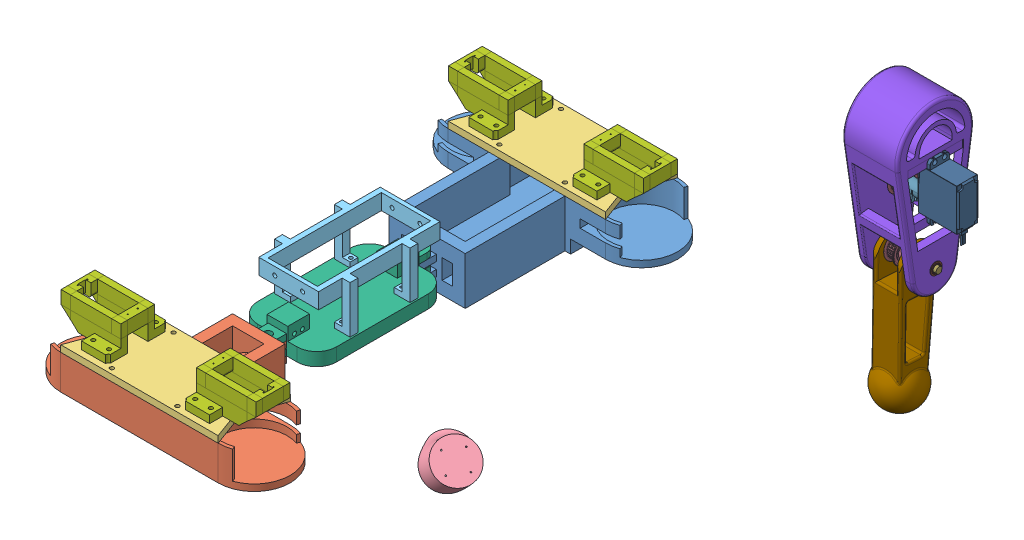
SolidWorks assembly Test 1, configuration Default. Lengths in mm.
Overall size (344.52 269.69 604.87).
26 component instances, 15 part files, 27 mates.
Components (placement in the parent):
- Battery hipshoulder joint V2-1: Battery hipshoulder joint V2 [Default] at (116.5566 143.9186 133.8878) size (222.25 46.04 184.15)
- static and shortened hipjoint-1: static and shortened hipjoint [Default] at (143.8691 143.9186 481.5862) x (-1 0 0) z (0 0 -1) size (222.2 33.34 133.35)
- servo mount plate hips V3 for battery-1: servo mount plate hips V3 for battery [Default] at (91.8917 170.9061 427.5781) x (-1 0 0) z (0 0 -1) size (152.35 6.35 69.85)
- servo mount plate hips V3 for battery-2: servo mount plate hips V3 for battery [Default] at (168.534 170.9061 187.896) size (152.35 6.35 69.85)
- Boelt Neck-1: Boelt Neck [Default] at (288.7574 131.5413 387.3682) x (0.766889 -0.527675 -0.365294) z (0.098402 -0.465781 0.879412) size (38.52 95.25 58.14)
- teensy spine base holder-1: teensy spine base holder [Default] at (130.2253 186.7811 326.9385) x (0 0 -1) z (1 0 0) size (117.54 45.72 73.11)
- chassis base v1-1: chassis base v1 [Default] at (130.2253 143.6011 333.137) x (0 0 -1) z (1 0 0) size (162.56 25.4 76.2)
- servomount v1-1: servomount v1 [Default] at (133.2266 146.0141 495.2557) size (57.78 27.96 58.16)
- servomount v1-2: servomount v1 [Default] at (133.2016 146.0141 120.2183) size (57.78 27.96 58.16)
- servomount v1-3: servomount v1 [Default] at (127.1991 146.0141 120.2183) x (-1 0 0) z (0 0 -1) size (57.78 27.96 58.16)
- servomount v1-4: servomount v1 [Default] at (127.2241 146.0141 495.2557) x (-1 0 0) z (0 0 -1) size (57.78 27.96 58.16)
- LegDesign_v4_with_hardware-1: LegDesign_v4_with_hardware [Default] at (328.8952 169.9097 -56.2942) size (106.43 269.69 74.17)
  - Thigh_4-1: Thigh_4 [Default] at (-48.9335 29.868 18.7213) size (53.34 161.92 74.17)
  - Shin_4-1: Shin_4 [Default] at (-25.0091 -180.039 24.4157) x (0 -0.053 -0.998595) z (1 0 0) size (43.18 142.24 43.18)
  - sunfounder_20kgSLDPRT-2: sunfounder_20kgSLDPRT [Default] at (15.326 -5.8432 27.0019) x (0 0 -1) z (0 1 0) size (20 46.03 62.2)
  - 57155K472_Flanged Ball Bearing-1: 57155K472_Flanged Ball Bearing [57155K472] at (3.7565 -72.748 18.7213) x (0 0 1) z (-1 0 0) size (11.2 11.2 2.5)
  - shaft-1: shaft [Default] at (27.8774 -72.748 18.7213) x (0 0.983181 -0.182636) z (0 0.182636 0.983181) size (7 60 7)
  - 1375K138_MXL Series Timing Belt Pulley-1: 1375K138_MXL Series Timing Belt Pulley [1375K138] at (-25.7841 -72.748 18.7213) x (-1 0 0) z (0 0.885769 -0.464126) size (17.5 24 24)
  - servoCoupler-1: servoCoupler [Default] at (-8.6803 -60.6446 51.7651) x (0 -0.965642 0.259874) z (0 -0.259874 -0.965642) size (17.1 16.07 14.01)
    - 4001-0025-0006 assembly.STEP-1: 4001-0025-0006 assembly.STEP [Default] at origin size (17.1 16.07 14.01)
      - 4001-0025-0006.STEP-1: 4001-0025-0006.STEP [Default] at (-51.8616 6.0214 22.0431) size (16.03 15.5 12)
      - 2800-0004-0008_90128A207.STEP-1: 2800-0004-0008_90128A207.STEP [Default] at (-45.3332 10.0214 18.0431) x (-0.923728 -0.383049 0) z (0 0 -1) size (7 7 12.01)
  - 57155K472_Flanged Ball Bearing-2: 57155K472_Flanged Ball Bearing [57155K472] at (-48.2835 -72.748 18.7213) x (0 0 1) z (1 0 0) size (11.2 11.2 2.5)
  - shaft-2: shaft [Default] at (8.2982 -16.2932 17.0019) x (0 0.921067 -0.389403) z (0 0.389403 0.921067) size (7 60 7)
  - 1375K138_MXL Series Timing Belt Pulley-2: 1375K138_MXL Series Timing Belt Pulley [1375K138] at (-31.4518 -16.2932 17.0019) x (1 0 0) z (0 0.148445 -0.988921) size (17.5 24 24)
  - 57155K472_Flanged Ball Bearing-3: 57155K472_Flanged Ball Bearing [57155K472] at (-48.2835 -16.2932 17.0019) x (0 0 1) z (1 0 0) size (11.2 11.2 2.5)
Mates (geometry in assembly coordinates):
- Coincident1: coincident aligned: plane of static and shortened hipjoint-1 through (143.8691 170.9061 530.2107) normal (0 0 1); plane of servo mount plate hips V3 for battery-1 through (130.2253 177.2561 530.2107) normal (0 0 1)
- Coincident2: coincident anti-aligned: line of static and shortened hipjoint-1 through (54.0503 170.9061 530.2107) axis (0 -1 0); line of servo mount plate hips V3 for battery-1 through (54.0503 170.9061 530.2107) axis (0 1 0)
- Coincident3: coincident anti-aligned: plane of static and shortened hipjoint-1 through (143.8691 170.9061 481.5862) normal (0 1 0); plane of servo mount plate hips V3 for battery-1 through (91.8917 170.9061 427.5781) normal (0 -1 0)
- Coincident4: coincident aligned: plane of Battery hipshoulder joint V2-1 through (116.5566 170.9061 85.2633) normal (0 0 -1); plane of servo mount plate hips V3 for battery-2 through (130.2004 177.2561 85.2633) normal (0 0 -1)
- Coincident5: coincident anti-aligned: line of Battery hipshoulder joint V2-1 through (54.0253 170.9061 85.2633) axis (0 -1 0); line of servo mount plate hips V3 for battery-2 through (54.0253 170.9061 85.2633) axis (0 1 0)
- Coincident7: coincident anti-aligned: plane of Battery hipshoulder joint V2-1 through (116.5566 170.9061 133.8878) normal (0 1 0); plane of servo mount plate hips V3 for battery-2 through (168.534 170.9061 187.896) normal (0 -1 0)
- Concentric1: concentric aligned: cylinder of Battery hipshoulder joint V2-1 through (130.2253 125.8846 260.5233) axis (0 1 0) radius 3.81; cylinder of chassis base v1-1 through (130.2253 139.5371 260.5233) axis (0 1 0) radius 3.81
- Coincident9: coincident anti-aligned: plane of Battery hipshoulder joint V2-1 through (142.4173 156.3646 251.6333) normal (0 1 0); plane of chassis base v1-1 through (168.3253 156.3646 269.637) normal (0 -1 0)
- Concentric2: concentric aligned: cylinder of static and shortened hipjoint-1 through (130.2253 125.8846 405.7507) axis (0 1 0) radius 3.81; cylinder of chassis base v1-1 through (130.2253 139.5371 405.7507) axis (0 1 0) radius 3.81
- Coincident10: coincident anti-aligned: plane of static and shortened hipjoint-1 through (118.0333 156.3646 414.6407) normal (0 1 0); plane of chassis base v1-1 through (168.3253 156.3646 396.637) normal (0 -1 0)
- Concentric3: concentric aligned: cylinder of teensy spine base holder-1 through (154.7363 161.3811 301.0378) axis (0 -1 0) radius 1.269; cylinder of chassis base v1-1 through (154.7363 169.0011 301.0378) axis (0 -1 0) radius 1.5453
- Concentric4: concentric aligned: cylinder of teensy spine base holder-1 through (105.7143 161.3811 359.0378) axis (0 -1 0) radius 1.6712; cylinder of chassis base v1-1 through (105.7143 169.0011 359.0378) axis (0 -1 0) radius 1.7336
- Coincident11: coincident anti-aligned: plane of teensy spine base holder-1 through (130.2253 156.3011 326.9385) normal (0 -1 0); plane of chassis base v1-1 through (120.1953 156.3011 375.6607) normal (0 1 0)
- Parallel1: parallel anti-aligned: plane of static and shortened hipjoint-1 through (143.8691 143.9186 396.8607) normal (0 0 -1); plane of chassis base v1-1 through (168.3253 156.3011 396.637) normal (0 0 1)
- Parallel2: parallel anti-aligned: plane of Battery hipshoulder joint V2-1 through (116.5566 143.9186 269.4133) normal (0 0 1); plane of chassis base v1-1 through (168.3253 156.3011 269.637) normal (0 0 -1)
- Coincident14: coincident anti-aligned: plane of servo mount plate hips V3 for battery-1 through (91.8917 177.2561 427.5781) normal (0 1 0); plane of servomount v1-1 through (166.8604 177.2561 566.0952) normal (0 -1 0)
- Concentric5: concentric anti-aligned: cylinder of servo mount plate hips V3 for battery-1 through (171.9404 177.2561 517.9857) axis (0 -1 0) radius 1.27; cylinder of servomount v1-1 through (171.9404 171.9259 517.9857) axis (0 1 0) radius 1.8415
- Parallel4: parallel aligned: plane of servo mount plate hips V3 for battery-1 through (130.2253 177.2561 460.3607) normal (0 0 -1); plane of servomount v1-1 through (133.2266 146.0141 466.1757) normal (0 0 -1)
- Concentric8: concentric anti-aligned: cylinder of servo mount plate hips V3 for battery-1 through (88.5103 177.2561 517.9857) axis (0 -1 0) radius 1.27; cylinder of servomount v1-4 through (88.5103 171.9259 517.9857) axis (0 1 0) radius 1.8415
- Coincident16: coincident anti-aligned: plane of servo mount plate hips V3 for battery-1 through (91.8917 177.2561 427.5781) normal (0 1 0); plane of servomount v1-4 through (93.5903 177.2561 424.4163) normal (0 -1 0)
- Parallel5: parallel aligned: plane of servo mount plate hips V3 for battery-1 through (130.2253 177.2561 460.3607) normal (0 0 -1); plane of servomount v1-4 through (127.2241 146.0141 466.1757) normal (0 0 -1)
- Concentric9: concentric anti-aligned: cylinder of servo mount plate hips V3 for battery-2 through (88.4853 177.2561 97.4883) axis (0 -1 0) radius 1.27; cylinder of servomount v1-3 through (88.4853 171.9259 97.4883) axis (0 1 0) radius 1.8415
- Parallel6: parallel aligned: plane of servo mount plate hips V3 for battery-2 through (130.2004 177.2561 155.1133) normal (0 0 1); plane of servomount v1-3 through (127.1991 146.0141 149.2983) normal (0 0 1)
- Coincident19: coincident anti-aligned: plane of servo mount plate hips V3 for battery-2 through (168.534 177.2561 187.896) normal (0 1 0); plane of servomount v1-3 through (93.5653 177.2561 49.3788) normal (0 -1 0)
- Concentric10: concentric anti-aligned: cylinder of servo mount plate hips V3 for battery-2 through (171.9154 177.2561 97.4883) axis (0 -1 0) radius 1.27; cylinder of servomount v1-2 through (171.9154 171.9259 97.4883) axis (0 1 0) radius 1.8415
- Parallel7: parallel aligned: plane of servo mount plate hips V3 for battery-2 through (130.2004 177.2561 155.1133) normal (0 0 1); plane of servomount v1-2 through (133.2016 146.0141 149.2983) normal (0 0 1)
- Coincident21: coincident anti-aligned: plane of servo mount plate hips V3 for battery-2 through (168.534 177.2561 187.896) normal (0 1 0); plane of servomount v1-2 through (166.8354 177.2561 191.0577) normal (0 -1 0)
